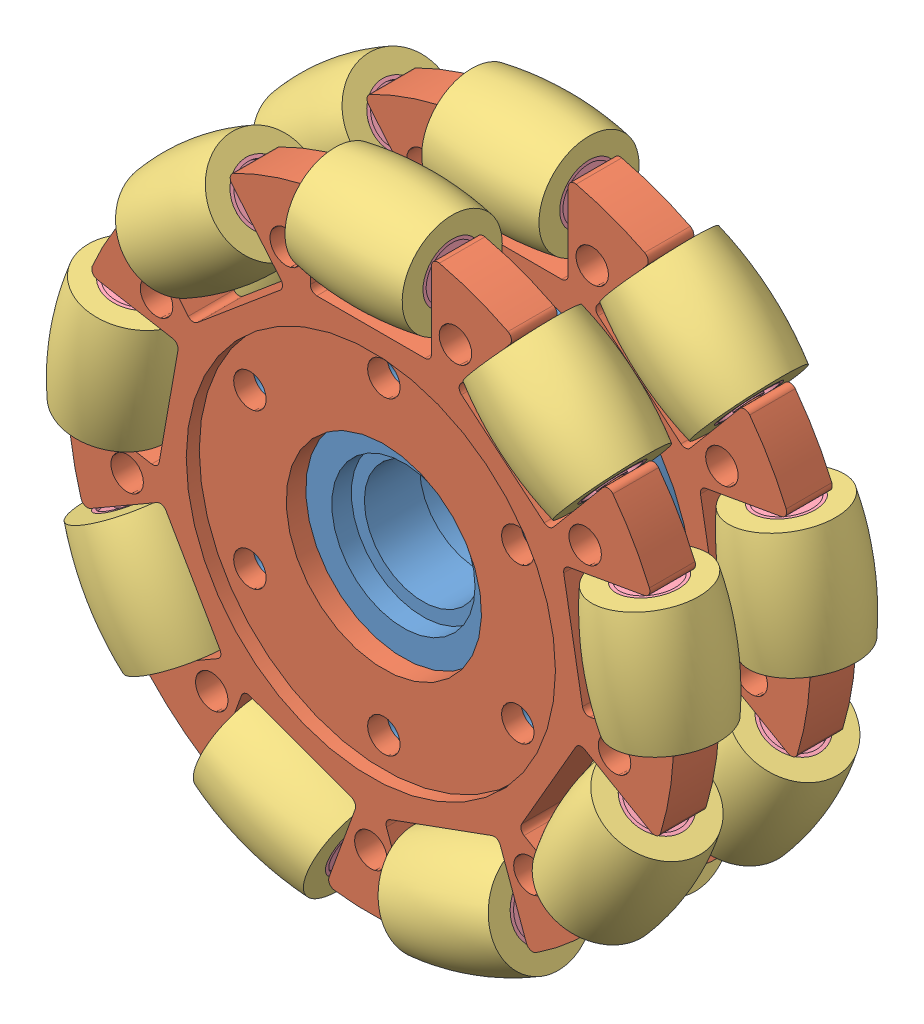
SolidWorks assembly 100mm Omni Wheel, configuration Default. Lengths in mm.
Overall size (130.79 130.79 55.1).
60 component instances, 5 part files, 6 mates.
Components (placement in the parent):
- Core-1: Core [Default] at origin size (56 56 18)
- Single Side-2: Single Side [Default] at (0 0 10.5) x (-0.5 0.866025 0) z (0 0 1) size (107.72 106.08 23.21)
  - Frame-1: Frame [Default] at origin size (92.88 91.83 7)
  - Roller_New-1: Roller_New [預設] at (0 41.5 0) x (1 0 0) z (0 -0.498092 0.867124) size (18 17 17)
  - MR93zz_3x9x4mm-1: MR93zz_3x9x4mm [預設] at (7 41.5 0) x (0 0 -1) z (1 0 0) size (9 9 4)
  - MR93zz_3x9x4mm-2: MR93zz_3x9x4mm [預設] at (-7 41.5 0) x (0 0 1) z (-1 0 0) size (9 9 4)
  - Roller_New-2: Roller_New [預設] at (-26.6757 31.7908 0) x (0.766044 0.642788 0) z (0.320168 -0.381561 0.867124) size (18 17 17)
  - Roller_New-3: Roller_New [預設] at (-40.8695 7.2064 0) x (0.173648 0.984808 0) z (0.490525 -0.086493 0.867124) size (18 17 17)
  - Roller_New-4: Roller_New [預設] at (-35.9401 -20.75 0) x (-0.5 0.866025 0) z (0.431361 0.249046 0.867124) size (18 17 17)
  - Roller_New-5: Roller_New [預設] at (-14.1938 -38.9972 0) x (-0.939693 0.34202 0) z (0.170358 0.468054 0.867124) size (18 17 17)
  - Roller_New-6: Roller_New [預設] at (14.1938 -38.9972 0) x (-0.939693 -0.34202 0) z (-0.170358 0.468054 0.867124) size (18 17 17)
  - Roller_New-7: Roller_New [預設] at (35.9401 -20.75 0) x (-0.5 -0.866025 0) z (-0.431361 0.249046 0.867124) size (18 17 17)
  - Roller_New-8: Roller_New [預設] at (40.8695 7.2064 0) x (0.173648 -0.984808 0) z (-0.490525 -0.086493 0.867124) size (18 17 17)
  - Roller_New-9: Roller_New [預設] at (26.6757 31.7908 0) x (0.766044 -0.642788 0) z (-0.320168 -0.381561 0.867124) size (18 17 17)
  - MR93zz_3x9x4mm-3: MR93zz_3x9x4mm [預設] at (-32.038 27.2913 0) x (0 0 1) z (-0.766044 -0.642788 0) size (9 9 4)
  - MR93zz_3x9x4mm-4: MR93zz_3x9x4mm [預設] at (-42.0851 0.3127 0) x (0 0 1) z (-0.173648 -0.984808 0) size (9 9 4)
  - MR93zz_3x9x4mm-5: MR93zz_3x9x4mm [預設] at (-32.4401 -26.8122 0) x (0 0 1) z (0.5 -0.866025 0) size (9 9 4)
  - MR93zz_3x9x4mm-6: MR93zz_3x9x4mm [預設] at (-7.616 -41.3914 0) x (0 0 1) z (0.939693 -0.34202 0) size (9 9 4)
  - MR93zz_3x9x4mm-7: MR93zz_3x9x4mm [預設] at (20.7717 -36.6031 0) x (0 0 1) z (0.939693 0.34202 0) size (9 9 4)
  - MR93zz_3x9x4mm-8: MR93zz_3x9x4mm [預設] at (39.4401 -14.6878 0) x (0 0 1) z (0.5 0.866025 0) size (9 9 4)
  - MR93zz_3x9x4mm-9: MR93zz_3x9x4mm [預設] at (39.654 14.1001 0) x (0 0 1) z (-0.173648 0.984808 0) size (9 9 4)
  - MR93zz_3x9x4mm-10: MR93zz_3x9x4mm [預設] at (21.3134 36.2904 0) x (0 0 1) z (-0.766044 0.642788 0) size (9 9 4)
  - MR93zz_3x9x4mm-11: MR93zz_3x9x4mm [預設] at (-21.3134 36.2904 0) x (0 0 -1) z (0.766044 0.642788 0) size (9 9 4)
  - MR93zz_3x9x4mm-12: MR93zz_3x9x4mm [預設] at (-39.654 14.1001 0) x (0 0 -1) z (0.173648 0.984808 0) size (9 9 4)
  - MR93zz_3x9x4mm-13: MR93zz_3x9x4mm [預設] at (-39.4401 -14.6878 0) x (0 0 -1) z (-0.5 0.866025 0) size (9 9 4)
  - MR93zz_3x9x4mm-14: MR93zz_3x9x4mm [預設] at (-20.7717 -36.6031 0) x (0 0 -1) z (-0.939693 0.34202 0) size (9 9 4)
  - MR93zz_3x9x4mm-15: MR93zz_3x9x4mm [預設] at (7.616 -41.3914 0) x (0 0 -1) z (-0.939693 -0.34202 0) size (9 9 4)
  - MR93zz_3x9x4mm-16: MR93zz_3x9x4mm [預設] at (32.4401 -26.8122 0) x (0 0 -1) z (-0.5 -0.866025 0) size (9 9 4)
  - MR93zz_3x9x4mm-17: MR93zz_3x9x4mm [預設] at (42.0851 0.3127 0) x (0 0 -1) z (0.173648 -0.984808 0) size (9 9 4)
  - MR93zz_3x9x4mm-18: MR93zz_3x9x4mm [預設] at (32.038 27.2913 0) x (0 0 -1) z (0.766044 -0.642788 0) size (9 9 4)
- 8mm Hub-1: 8mm Hub [預設] at (0 0 -12) x (-0.5 0.866025 0) z (0 0 -1) size (56.7 56.7 26)
- Single Side-3: Single Side [Default] at (0 0 -10.5) x (-0.5 0.866025 0) z (0 0 1) size (107.72 106.08 23.21)
  - Frame-1: Frame [Default] at origin size (92.88 91.83 7)
  - Roller_New-1: Roller_New [預設] at (0 41.5 0) x (1 0 0) z (0 -0.498092 0.867124) size (18 17 17)
  - MR93zz_3x9x4mm-1: MR93zz_3x9x4mm [預設] at (7 41.5 0) x (0 0 -1) z (1 0 0) size (9 9 4)
  - MR93zz_3x9x4mm-2: MR93zz_3x9x4mm [預設] at (-7 41.5 0) x (0 0 1) z (-1 0 0) size (9 9 4)
  - Roller_New-2: Roller_New [預設] at (-26.6757 31.7908 0) x (0.766044 0.642788 0) z (0.320168 -0.381561 0.867124) size (18 17 17)
  - Roller_New-3: Roller_New [預設] at (-40.8695 7.2064 0) x (0.173648 0.984808 0) z (0.490525 -0.086493 0.867124) size (18 17 17)
  - Roller_New-4: Roller_New [預設] at (-35.9401 -20.75 0) x (-0.5 0.866025 0) z (0.431361 0.249046 0.867124) size (18 17 17)
  - Roller_New-5: Roller_New [預設] at (-14.1938 -38.9972 0) x (-0.939693 0.34202 0) z (0.170358 0.468054 0.867124) size (18 17 17)
  - Roller_New-6: Roller_New [預設] at (14.1938 -38.9972 0) x (-0.939693 -0.34202 0) z (-0.170358 0.468054 0.867124) size (18 17 17)
  - Roller_New-7: Roller_New [預設] at (35.9401 -20.75 0) x (-0.5 -0.866025 0) z (-0.431361 0.249046 0.867124) size (18 17 17)
  - Roller_New-8: Roller_New [預設] at (40.8695 7.2064 0) x (0.173648 -0.984808 0) z (-0.490525 -0.086493 0.867124) size (18 17 17)
  - Roller_New-9: Roller_New [預設] at (26.6757 31.7908 0) x (0.766044 -0.642788 0) z (-0.320168 -0.381561 0.867124) size (18 17 17)
  - MR93zz_3x9x4mm-3: MR93zz_3x9x4mm [預設] at (-32.038 27.2913 0) x (0 0 1) z (-0.766044 -0.642788 0) size (9 9 4)
  - MR93zz_3x9x4mm-4: MR93zz_3x9x4mm [預設] at (-42.0851 0.3127 0) x (0 0 1) z (-0.173648 -0.984808 0) size (9 9 4)
  - MR93zz_3x9x4mm-5: MR93zz_3x9x4mm [預設] at (-32.4401 -26.8122 0) x (0 0 1) z (0.5 -0.866025 0) size (9 9 4)
  - MR93zz_3x9x4mm-6: MR93zz_3x9x4mm [預設] at (-7.616 -41.3914 0) x (0 0 1) z (0.939693 -0.34202 0) size (9 9 4)
  - MR93zz_3x9x4mm-7: MR93zz_3x9x4mm [預設] at (20.7717 -36.6031 0) x (0 0 1) z (0.939693 0.34202 0) size (9 9 4)
  - MR93zz_3x9x4mm-8: MR93zz_3x9x4mm [預設] at (39.4401 -14.6878 0) x (0 0 1) z (0.5 0.866025 0) size (9 9 4)
  - MR93zz_3x9x4mm-9: MR93zz_3x9x4mm [預設] at (39.654 14.1001 0) x (0 0 1) z (-0.173648 0.984808 0) size (9 9 4)
  - MR93zz_3x9x4mm-10: MR93zz_3x9x4mm [預設] at (21.3134 36.2904 0) x (0 0 1) z (-0.766044 0.642788 0) size (9 9 4)
  - MR93zz_3x9x4mm-11: MR93zz_3x9x4mm [預設] at (-21.3134 36.2904 0) x (0 0 -1) z (0.766044 0.642788 0) size (9 9 4)
  - MR93zz_3x9x4mm-12: MR93zz_3x9x4mm [預設] at (-39.654 14.1001 0) x (0 0 -1) z (0.173648 0.984808 0) size (9 9 4)
  - MR93zz_3x9x4mm-13: MR93zz_3x9x4mm [預設] at (-39.4401 -14.6878 0) x (0 0 -1) z (-0.5 0.866025 0) size (9 9 4)
  - MR93zz_3x9x4mm-14: MR93zz_3x9x4mm [預設] at (-20.7717 -36.6031 0) x (0 0 -1) z (-0.939693 0.34202 0) size (9 9 4)
  - MR93zz_3x9x4mm-15: MR93zz_3x9x4mm [預設] at (7.616 -41.3914 0) x (0 0 -1) z (-0.939693 -0.34202 0) size (9 9 4)
  - MR93zz_3x9x4mm-16: MR93zz_3x9x4mm [預設] at (32.4401 -26.8122 0) x (0 0 -1) z (-0.5 -0.866025 0) size (9 9 4)
  - MR93zz_3x9x4mm-17: MR93zz_3x9x4mm [預設] at (42.0851 0.3127 0) x (0 0 -1) z (0.173648 -0.984808 0) size (9 9 4)
  - MR93zz_3x9x4mm-18: MR93zz_3x9x4mm [預設] at (32.038 27.2913 0) x (0 0 -1) z (0.766044 -0.642788 0) size (9 9 4)
Mates (geometry in assembly coordinates):
- 重合/共線/共點213: coordinate: point of Core-1; point of assembly
- 重合/共線/共點215: coincident anti-aligned: circle of Core-1; circle of Single Side-2/Frame-1
- 重合/共線/共點216: coincident anti-aligned: circle of Core-1; circle of Single Side-2/Frame-1
- 同軸心1: concentric anti-aligned: circle of 8mm Hub-1; circle of Single Side-3/Frame-1
- 同軸心2: concentric anti-aligned: circle of 8mm Hub-1; circle of Single Side-3/Frame-1
- 重合/共線/共點217: coincident anti-aligned: plane of 8mm Hub-1 through (0 0 -12) normal (0 0 1); plane of Single Side-3/Frame-1 through (0 0 -12) normal (0 0 -1)
